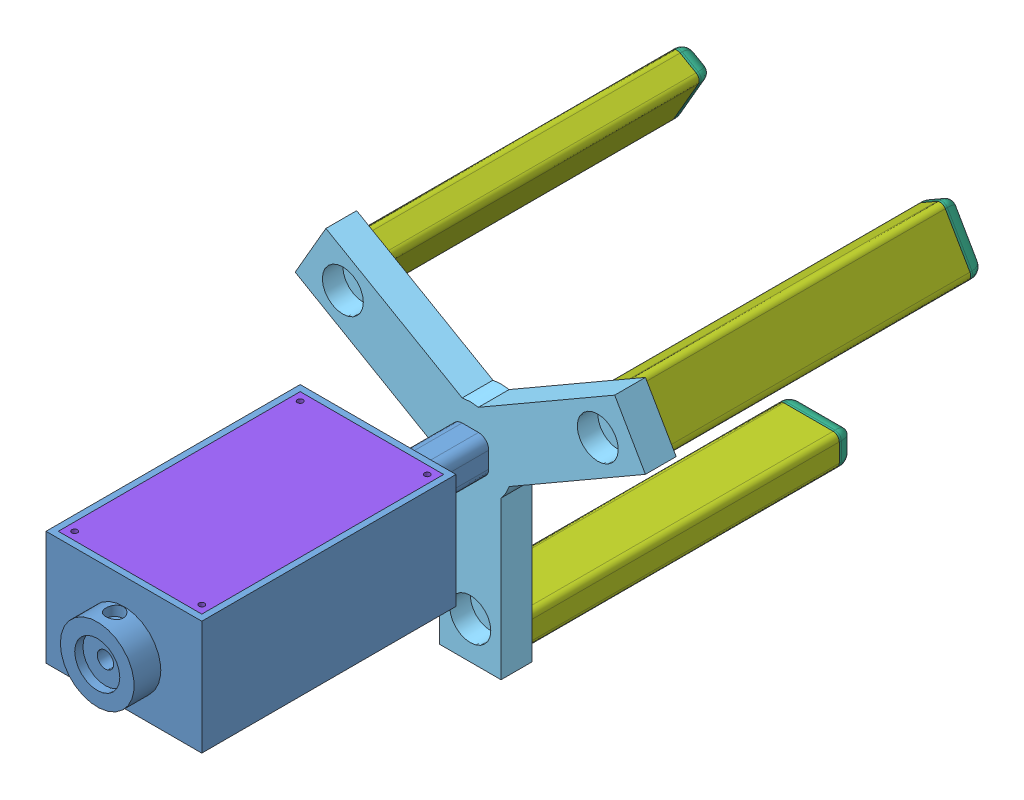
SolidWorks assembly NewEndEffector, configuration Default. Lengths in mm.
Overall size (170.88 147.99 355).
27 component instances, 9 part files, 2 mates.
Components (placement in the parent):
- GrapperWithServos-1: GrapperWithServos [Default] at (-20.6091 -66.5283 -141.4389) size (170.88 147.99 355)
  - ServoHolder-1: ServoHolder [Default] at (20.6091 41.5283 66.4389) size (76 55.75 187)
  - ServoWithHornCover-1: ServoWithHornCover [Default] at (-47.2507 32.9202 59.0729) x (0 0 -1) z (1 0 0) size (60.01 49.75 41.52) (flexible)
    - MG996R-1: MG996R [Default] at (22.884 11.6081 50.6098) size (53.5 42.75 19.5)
    - ServoHornWithGroove-1: ServoHornWithGroove [Default] at (12.384 56.3581 50.6098) x (0.653288 0 0.75711) z (0.75711 0 -0.653288) size (30 9.5 30)
    - ServoCover-1: ServoCover [Default] at (34.0772 41.3581 67.8598) x (-1 0 0) z (0 0 -1) size (57.5 20 34.5)
  - ServoWithHornCover-2: ServoWithHornCover [Default] at (-12.7507 32.9202 59.0729) x (0 0 -1) z (1 0 0) size (60.01 49.75 41.52) (flexible)
    - MG996R-1: MG996R [Default] at (22.884 11.6081 50.6098) size (53.5 42.75 19.5)
    - ServoHornWithGroove-1: ServoHornWithGroove [Default] at (12.384 56.3581 50.6098) x (0.586538 0 0.809922) z (0.809922 0 -0.586538) size (30 9.5 30)
    - ServoCover-1: ServoCover [Default] at (34.0772 41.3581 67.8598) x (-1 0 0) z (0 0 -1) size (57.5 20 34.5)
  - 3GripperAssembly-1: 3GripperAssembly [Default] at (-30.3334 -49.3942 19.9719) x (1 0 0) z (0 1 0) size (170.88 173 147.99)
    - EndEffector3Grapper-1: EndEffector3Grapper [Default] at (50.9425 60.533 115.9226) size (170.88 20 147.99)
    - FingerAssembly-1: FingerAssembly [Default] at (105.0348 198.5242 138.6511) x (-0.5 0 0.866025) z (0 1 0) size (30 15 158)
      - FingerTip-1: FingerTip [Default] at (7.3627 17.1904 24.0088) size (30 15 11)
      - Finger-1: Finger [Default] at (7.3627 18.2904 -122.9912) x (1 0 0) z (0 -1 0) size (30 150 15)
    - FingerAssembly-2: FingerAssembly [Default] at (4.2129 198.5242 151.4036) x (-0.5 0 -0.866025) z (0 1 0) size (30 15 158)
      - FingerTip-1: FingerTip [Default] at (7.3627 17.1904 24.0088) size (30 15 11)
      - Finger-1: Finger [Default] at (7.3627 18.2904 -122.9912) x (1 0 0) z (0 -1 0) size (30 150 15)
    - FingerAssembly-3: FingerAssembly [Default] at (43.5799 198.5242 57.713) x (1 0 0) z (0 1 0) size (30 15 158)
      - FingerTip-1: FingerTip [Default] at (7.3627 17.1904 24.0088) size (30 15 11)
      - Finger-1: Finger [Default] at (7.3627 18.2904 -122.9912) x (1 0 0) z (0 -1 0) size (30 150 15)
  - ServoWithHornCover-4: ServoWithHornCover [Default] at (-30.0007 32.9202 119.5729) x (0 0 -1) z (1 0 0) size (60.01 49.75 41.52)
    - MG996R-1: MG996R [Default] at (22.884 11.6081 50.6098) size (53.5 42.75 19.5)
    - ServoHornWithGroove-1: ServoHornWithGroove [Default] at (12.384 56.3581 50.6098) x (-0.837169 0 -0.546944) z (-0.546944 0 0.837169) size (30 9.5 30)
    - ServoCover-1: ServoCover [Default] at (34.0772 41.3581 67.8598) x (-1 0 0) z (0 0 -1) size (57.5 20 34.5)
  - ServoHolderCover-1: ServoHolderCover [Default] at (20.6091 94.2783 66.4389) x (0 0 -1) z (1 0 0) size (118 3 70)
  - socket head cap screw_iso-1: socket head cap screw_iso [ISO 4762 M6 x 20 - 20S] at (20.6091 66.5283 -55.5611) x (0 0 1) z (-0.923728 -0.383049 0) size (26 10 10)
Mates (geometry in assembly coordinates):
- Distance1: distance = 0 mm: cylinder of assembly; point of assembly; cylinder of GrapperWithServos-1/ServoHolder-1 through (0 0 -4) axis (0 0 1) radius 11
- Coincident2: coincident: plane of GrapperWithServos-1/ServoHolder-1 through (0 0 0) normal (0 0 1)
